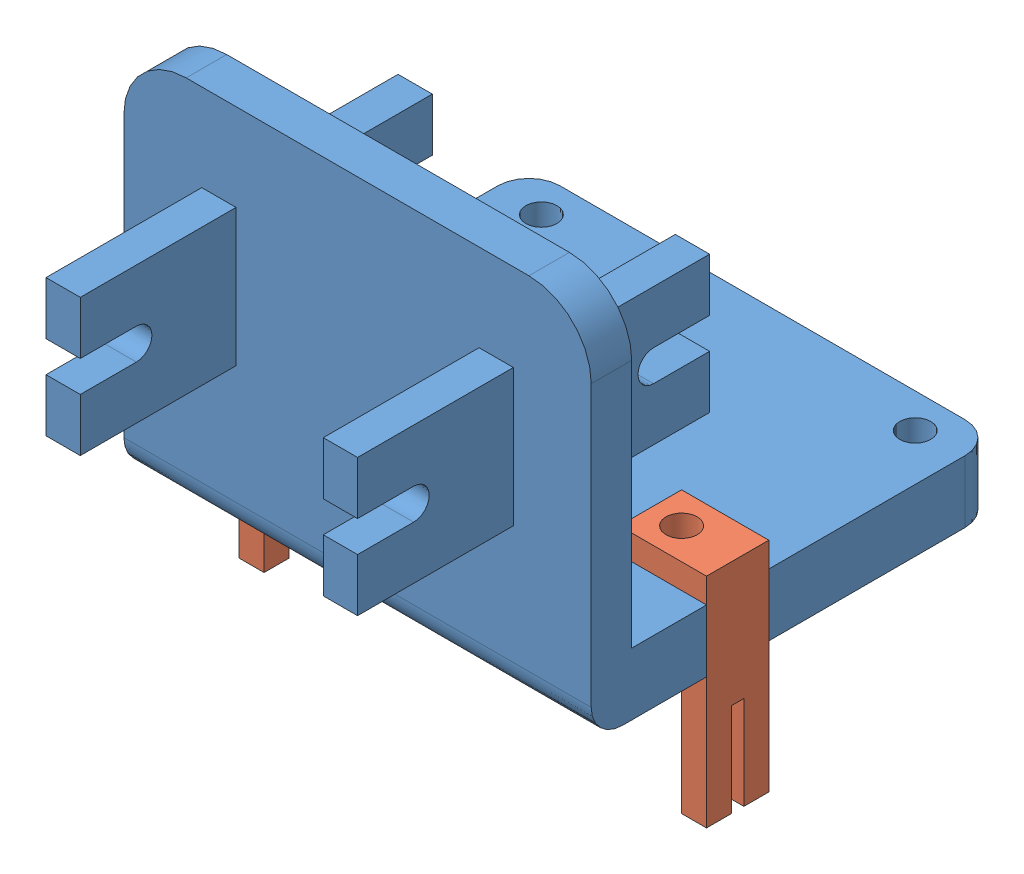
SolidWorks assembly laser_mount_v2_assem, configuration Default. Lengths in mm.
Overall size (75 81 90).
3 component instances, 2 part files, 6 mates.
Components (placement in the parent):
- centre_laser_mount_v2-1: centre_laser_mount_v2 [Default] at (16.5729 46.747 86.7224) size (75 60 90)
- mount_attachment-1: mount_attachment [Default] at (-20.9271 25.747 95.7224) x (0 1 0) z (1 0 0) size (35 10 14)
- mount_attachment-2: mount_attachment [Default] at (54.0729 25.747 105.7224) x (0 1 0) z (-1 0 0) size (35 10 14)
Mates (geometry in assembly coordinates):
- Coincident1: coincident anti-aligned: plane of centre_laser_mount_v2-1 through (-16.9271 46.747 86.7224) normal (-1 0 0); plane of mount_attachment-1 through (-16.9271 25.747 95.7224) normal (1 0 0)
- Coincident2: coincident anti-aligned: plane of centre_laser_mount_v2-1 through (16.5729 56.747 86.7224) normal (0 1 0); plane of mount_attachment-1 through (-6.9271 56.747 105.7224) normal (0 -1 0)
- Coincident3: coincident anti-aligned: plane of centre_laser_mount_v2-1 through (16.5729 46.747 105.7224) normal (0 0 -1); plane of mount_attachment-1 through (-16.9271 25.747 105.7224) normal (0 0 1)
- Coincident4: coincident anti-aligned: plane of centre_laser_mount_v2-1 through (16.5729 56.747 86.7224) normal (0 1 0); plane of mount_attachment-2 through (40.0729 56.747 95.7224) normal (0 -1 0)
- Coincident5: coincident anti-aligned: plane of centre_laser_mount_v2-1 through (16.5729 46.747 105.7224) normal (0 0 -1); plane of mount_attachment-2 through (50.0729 25.747 105.7224) normal (0 0 1)
- Coincident6: coincident anti-aligned: plane of centre_laser_mount_v2-1 through (50.0729 46.747 86.7224) normal (1 0 0); plane of mount_attachment-2 through (50.0729 25.747 105.7224) normal (-1 0 0)
